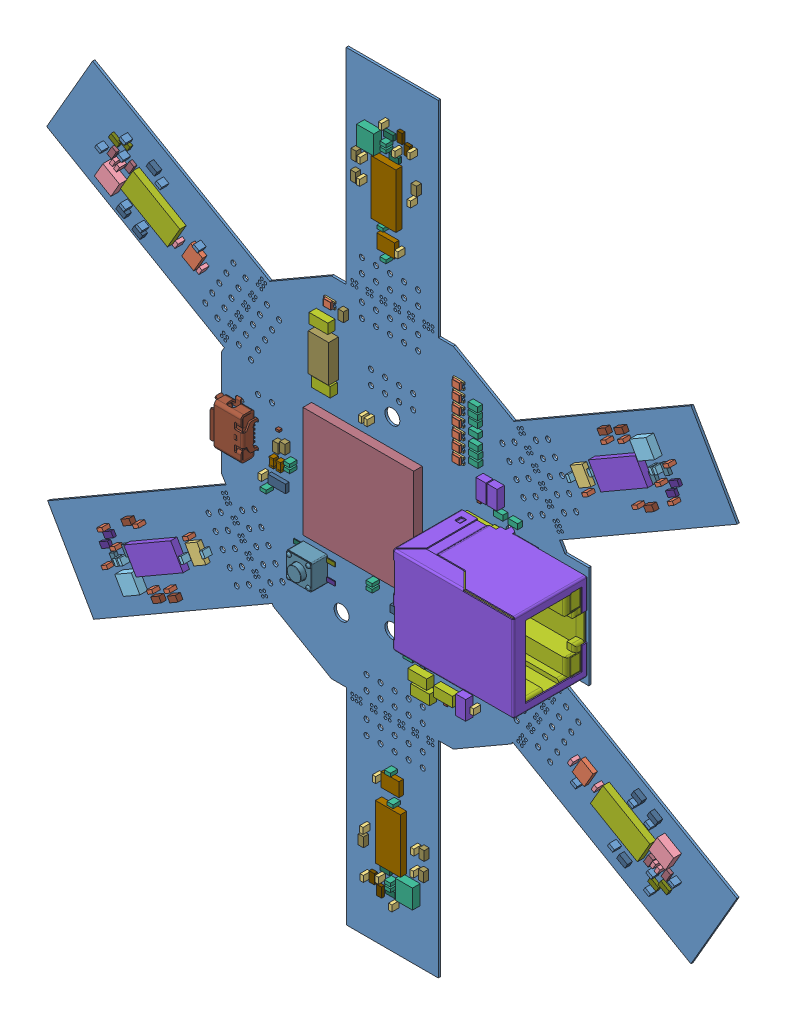
SolidWorks assembly PCB_Testplatine, configuration Standard. Lengths in mm.
Overall size (124.77 137.35 16.55).
623 component instances, 49 part files, 0 mates.
Components (placement in the parent):
- Board-1: Board [Standard] at (0 0 -0.4115) size (124.77 137.35 0.41)
- X_TDA_TDA6-1: X_TDA_TDA6 [Standard] at origin size (3.77 4.02 0.8)
  - 885545368-1: 885545368 [Standard] at (-35.3942 22.6879 0) size (3.77 4.02 0.8)
    - Extruded-1: Extruded [Standard] at origin size (3.77 4.02 0.8)
- X_TDA_TDA2-1: X_TDA_TDA2 [Standard] at origin size (3.77 4.02 0.8)
  - 885545640-1: 885545640 [Standard] at (34.8045 23.5121 0) size (3.77 4.02 0.8)
    - Extruded_2-1: Extruded_2 [Standard] at origin size (3.77 4.02 0.8)
- F1_TDA6-1: F1_TDA6 [Standard] at origin size (4.54 4.41 1.4)
  - 885544960-1: 885544960 [Standard] at (-50.1943 27.6532 0) size (4.54 4.41 1.4)
    - Extruded_3-1: Extruded_3 [Standard] at origin size (4.54 4.41 1.4)
- F1_TDA2-1: F1_TDA2 [Standard] at origin size (4.54 4.41 1.4)
  - 885545232-1: 885545232 [Standard] at (46.5047 33.8467 0) size (4.54 4.41 1.4)
    - Extruded_4-1: Extruded_4 [Standard] at origin size (4.54 4.41 1.4)
- F1_TDA1-1: F1_TDA1 [Standard] at origin size (3.1 3.45 1.4)
  - 885545096-1: 885545096 [Standard] at (-3.52 57.24 0) size (3.1 3.45 1.4)
    - Extruded_5-1: Extruded_5 [Standard] at origin size (3.1 3.45 1.4)
- T1-1: T1 [Standard] at origin size (21.84 15.88 16.55)
  - 7499010211A-1: 7499010211A [Standard] at (24.4001 -0.1251 6.7) x (0 -1 0) z (0 0 -1) size (15.88 21.84 16.55)
    - housing-1: housing [Standard] at origin size (15.48 21.44 16.35)
    - shielding-1: shielding [Standard] at origin size (15.88 21.84 16.25)
- X1-1: X1 [Standard] at origin size (3.2 2.5 0.8)
  - 885545504-1: 885545504 [Standard] at (10.5 -1.45 0) size (3.2 2.5 0.8)
    - Extruded_6-1: Extruded_6 [Standard] at origin size (3.2 2.5 0.8)
- X2-1: X2 [Standard] at origin size (3.2 1.5 0.65)
  - 885545776-1: 885545776 [Standard] at (-20.27 -5.32 0) size (3.2 1.5 0.65)
    - Extruded_7-1: Extruded_7 [Standard] at origin size (3.2 1.5 0.65)
- X_TDA_TDA1-1: X_TDA_TDA1 [Standard] at origin size (3.2 2.5 0.8)
  - 885545504-1: 885545504 [Standard] at (-0.42 41.94 0) size (3.2 2.5 0.8)
    - Extruded_6-1: Extruded_6 [Standard] at origin size (3.2 2.5 0.8)
- J1-1: J1 [Standard] at origin size (5.9 8.66 3.36)
  - 475900001-1: 475900001 [Standard] at (-26.2999 1.3001 0.26) x (0 1 0) z (1 0 0) size (8.66 3.36 5.9)
    - Open CASCADE STEP translator 6.8 1.11.1.1-1: Open CASCADE STEP translator 6.8 1.11.1.1 [Standard] at origin size (8.66 3.36 5.9)
- X_TDA_TDA5-1: X_TDA_TDA5 [Standard] at origin size (3.77 4.02 0.8)
  - 885545640-1: 885545640 [Standard] at (-34.8042 -23.4933 0) size (3.77 4.02 0.8)
    - Extruded_2-1: Extruded_2 [Standard] at origin size (3.77 4.02 0.8)
- X_TDA_TDA4-1: X_TDA_TDA4 [Standard] at origin size (3.2 2.5 0.8)
  - 885545504-1: 885545504 [Standard] at (0.38 -41.99 0) size (3.2 2.5 0.8)
    - Extruded_6-1: Extruded_6 [Standard] at origin size (3.2 2.5 0.8)
- X_TDA_TDA3-1: X_TDA_TDA3 [Standard] at origin size (3.77 4.02 0.8)
  - 885545368-1: 885545368 [Standard] at (35.1741 -22.7679 0) size (3.77 4.02 0.8)
    - Extruded-1: Extruded [Standard] at origin size (3.77 4.02 0.8)
- F1_TDA5-1: F1_TDA5 [Standard] at origin size (4.54 4.41 1.4)
  - 885545232-1: 885545232 [Standard] at (-46.5044 -33.8279 0) size (4.54 4.41 1.4)
    - Extruded_4-1: Extruded_4 [Standard] at origin size (4.54 4.41 1.4)
- F1_TDA4-1: F1_TDA4 [Standard] at origin size (3.1 3.45 1.4)
  - 885545096-1: 885545096 [Standard] at (3.48 -57.29 0) size (3.1 3.45 1.4)
    - Extruded_5-1: Extruded_5 [Standard] at origin size (3.1 3.45 1.4)
- F1_TDA3-1: F1_TDA3 [Standard] at origin size (4.54 4.41 1.4)
  - 885544960-1: 885544960 [Standard] at (49.9743 -27.7332 0) size (4.54 4.41 1.4)
    - Extruded_3-1: Extruded_3 [Standard] at origin size (4.54 4.41 1.4)
- X3-1: X3 [Standard] at origin size (2.5 3.2 0.8)
  - 885544824-1: 885544824 [Standard] at (15.2 -15.95 0) size (2.5 3.2 0.8)
    - Extruded_8-1: Extruded_8 [Standard] at origin size (2.5 3.2 0.8)
- IC3-1: IC3 [Standard] at origin size (4 4 0.85)
  - 885544688-1: 885544688 [Standard] at (8.35 -16.75 0) size (4 4 0.85)
    - Extruded_9-1: Extruded_9 [Standard] at origin size (4 4 0.85)
- S1-1: S1 [Standard] at origin size (7.5 4.5 3.8)
  - 430181038816-1: 430181038816 [Standard] at (-13.9849 -14.7149 0.01) x (1 0 0) z (0 0 1) size (7.5 4.5 3.8)
    - housing_2-1: housing_2 [Standard] at origin size (4.5 4.5 3.8)
    - pins-1: pins [Standard] at origin size (1.8 0.7 0.15)
    - pins_2-1: pins_2 [Standard] at origin size (1.8 0.7 0.15)
    - pins_3-1: pins_3 [Standard] at origin size (1.8 0.7 0.15)
    - pins_4-1: pins_4 [Standard] at origin size (1.8 0.7 0.15)
- Power-1: Power [Standard] at origin size (2 1.25 0.7)
  - WL-SMCW_0805_LED-1: WL-SMCW_0805_LED [Standard] at (-11.1648 27.3652 -0.02) x (1 0 0) z (0 0 1) size (2 1.25 0.7)
    - base-1: base [Standard] at (0.8 0 0) x (-1 0 0) z (0 0 1) size (0.4 1 0.3)
    - cover-1: cover [Standard] at (0 0 0.3) size (1.4 1.25 0.4)
    - housing_3-1: housing_3 [Standard] at origin size (2 1.25 0.3)
    - marking-1: marking [Standard] at (-0.8 0.525 0.26) size (0.4 0.48 0.04)
    - marking-2: marking [Standard] at (-0.8 -0.525 0.3) x (1 0 0) z (0 0 -1) size (0.4 0.48 0.04)
    - base_2-1: base_2 [Standard] at (-0.8 0 0) size (0.4 1 0.3)
- R26-1: R26 [Standard] at origin size (1.7 0.95 0.9)
  - 885541288-1: 885541288 [Standard] at (15.5 15.98 0) size (1.7 0.95 0.9)
    - Extruded_10-1: Extruded_10 [Standard] at origin size (1.7 0.95 0.9)
- R25-1: R25 [Standard] at origin size (1.7 0.95 0.9)
  - 885541288-1: 885541288 [Standard] at (15.5 17.26 0) size (1.7 0.95 0.9)
    - Extruded_10-1: Extruded_10 [Standard] at origin size (1.7 0.95 0.9)
- R24-1: R24 [Standard] at origin size (1.7 0.95 0.9)
  - 885541288-1: 885541288 [Standard] at (15.48 18.51 0) size (1.7 0.95 0.9)
    - Extruded_10-1: Extruded_10 [Standard] at origin size (1.7 0.95 0.9)
- D10-1: D10 [Standard] at origin size (2 1.25 0.7)
  - WL-SMCW_0805_LED-1: WL-SMCW_0805_LED [Standard] at (12.1102 14.6502 -0.02) x (1 0 0) z (0 0 1) size (2 1.25 0.7)
    - base-1: base [Standard] at (0.8 0 0) x (-1 0 0) z (0 0 1) size (0.4 1 0.3)
    - cover-1: cover [Standard] at (0 0 0.3) size (1.4 1.25 0.4)
    - housing_3-1: housing_3 [Standard] at origin size (2 1.25 0.3)
    - marking-1: marking [Standard] at (-0.8 0.525 0.26) size (0.4 0.48 0.04)
    - marking-2: marking [Standard] at (-0.8 -0.525 0.3) x (1 0 0) z (0 0 -1) size (0.4 0.48 0.04)
    - base_2-1: base_2 [Standard] at (-0.8 0 0) size (0.4 1 0.3)
- D9-1: D9 [Standard] at origin size (2 1.25 0.7)
  - WL-SMCW_0805_LED-1: WL-SMCW_0805_LED [Standard] at (12.1103 16.5697 -0.02) x (1 0 0) z (0 0 1) size (2 1.25 0.7)
    - base-1: base [Standard] at (0.8 0 0) x (-1 0 0) z (0 0 1) size (0.4 1 0.3)
    - cover-1: cover [Standard] at (0 0 0.3) size (1.4 1.25 0.4)
    - housing_3-1: housing_3 [Standard] at origin size (2 1.25 0.3)
    - marking-1: marking [Standard] at (-0.8 0.525 0.26) size (0.4 0.48 0.04)
    - marking-2: marking [Standard] at (-0.8 -0.525 0.3) x (1 0 0) z (0 0 -1) size (0.4 0.48 0.04)
    - base_2-1: base_2 [Standard] at (-0.8 0 0) size (0.4 1 0.3)
- D8-1: D8 [Standard] at origin size (2 1.25 0.7)
  - WL-SMCW_0805_LED-1: WL-SMCW_0805_LED [Standard] at (12.1002 18.5002 -0.02) x (1 0 0) z (0 0 1) size (2 1.25 0.7)
    - base-1: base [Standard] at (0.8 0 0) x (-1 0 0) z (0 0 1) size (0.4 1 0.3)
    - cover-1: cover [Standard] at (0 0 0.3) size (1.4 1.25 0.4)
    - housing_3-1: housing_3 [Standard] at origin size (2 1.25 0.3)
    - marking-1: marking [Standard] at (-0.8 0.525 0.26) size (0.4 0.48 0.04)
    - marking-2: marking [Standard] at (-0.8 -0.525 0.3) x (1 0 0) z (0 0 -1) size (0.4 0.48 0.04)
    - base_2-1: base_2 [Standard] at (-0.8 0 0) size (0.4 1 0.3)
- TDA5340_TDA6-1: TDA5340_TDA6 [Standard] at origin size (10.74 8.8 1.15)
  - 885544416-1: 885544416 [Standard] at (-42.5822 26.8379 0.05) size (10.74 8.8 1.15)
    - Extruded_11-1: Extruded_11 [Standard] at origin size (10.74 8.8 1.15)
- TDA5340_TDA5-1: TDA5340_TDA5 [Standard] at origin size (10.74 8.8 1.15)
  - 885544280-1: 885544280 [Standard] at (-41.9922 -27.6432 0.05) size (10.74 8.8 1.15)
    - Extruded_12-1: Extruded_12 [Standard] at origin size (10.74 8.8 1.15)
- TDA5340_TDA4-1: TDA5340_TDA4 [Standard] at origin size (4.5 9.8 1.15)
  - 885542512-1: 885542512 [Standard] at (0.38 -50.29 0.05) size (4.5 9.8 1.15)
    - Extruded_13-1: Extruded_13 [Standard] at origin size (4.5 9.8 1.15)
- TDA5340_TDA3-1: TDA5340_TDA3 [Standard] at origin size (10.74 8.8 1.15)
  - 885544416-1: 885544416 [Standard] at (42.3622 -26.9179 0.05) size (10.74 8.8 1.15)
    - Extruded_11-1: Extruded_11 [Standard] at origin size (10.74 8.8 1.15)
- TDA5340_TDA2-1: TDA5340_TDA2 [Standard] at origin size (10.74 8.8 1.15)
  - 885544280-1: 885544280 [Standard] at (41.9925 27.6621 0.05) size (10.74 8.8 1.15)
    - Extruded_12-1: Extruded_12 [Standard] at origin size (10.74 8.8 1.15)
- R3_TDA6-1: R3_TDA6 [Standard] at origin size (1.95 1.67 0.9)
  - 885544144-1: 885544144 [Standard] at (-42.6285 32.8576 0) size (1.95 1.67 0.9)
    - Extruded_14-1: Extruded_14 [Standard] at origin size (1.95 1.67 0.9)
- R3_TDA5-1: R3_TDA5 [Standard] at origin size (1.95 1.67 0.9)
  - 885544008-1: 885544008 [Standard] at (-47.2285 -24.6736 0) size (1.95 1.67 0.9)
    - Extruded_15-1: Extruded_15 [Standard] at origin size (1.95 1.67 0.9)
- R3_TDA4-1: R3_TDA4 [Standard] at origin size (0.95 1.7 0.9)
  - 885541560-1: 885541560 [Standard] at (-4.81 -53.34 0) size (0.95 1.7 0.9)
    - Extruded_16-1: Extruded_16 [Standard] at origin size (0.95 1.7 0.9)
- R3_TDA3-1: R3_TDA3 [Standard] at origin size (1.95 1.67 0.9)
  - 885544144-1: 885544144 [Standard] at (42.4085 -32.9376 0) size (1.95 1.67 0.9)
    - Extruded_14-1: Extruded_14 [Standard] at origin size (1.95 1.67 0.9)
- R3_TDA2-1: R3_TDA2 [Standard] at origin size (1.95 1.67 0.9)
  - 885544008-1: 885544008 [Standard] at (47.2288 24.6924 0) size (1.95 1.67 0.9)
    - Extruded_15-1: Extruded_15 [Standard] at origin size (1.95 1.67 0.9)
- R2_TDA6-1: R2_TDA6 [Standard] at origin size (1.95 1.67 0.9)
  - 885544144-1: 885544144 [Standard] at (-48.1169 23.4516 0) size (1.95 1.67 0.9)
    - Extruded_14-1: Extruded_14 [Standard] at origin size (1.95 1.67 0.9)
- R2_TDA5-1: R2_TDA5 [Standard] at origin size (1.95 1.67 0.9)
  - 885544008-1: 885544008 [Standard] at (-41.8269 -34.1296 0) size (1.95 1.67 0.9)
    - Extruded_15-1: Extruded_15 [Standard] at origin size (1.95 1.67 0.9)
- R2_TDA4-1: R2_TDA4 [Standard] at origin size (0.95 1.7 0.9)
  - 885541560-1: 885541560 [Standard] at (6.08 -53.39 0) size (0.95 1.7 0.9)
    - Extruded_16-1: Extruded_16 [Standard] at origin size (0.95 1.7 0.9)
- R2_TDA3-1: R2_TDA3 [Standard] at origin size (1.95 1.67 0.9)
  - 885544144-1: 885544144 [Standard] at (47.8969 -23.5316 0) size (1.95 1.67 0.9)
    - Extruded_14-1: Extruded_14 [Standard] at origin size (1.95 1.67 0.9)
- R2_TDA2-1: R2_TDA2 [Standard] at origin size (1.95 1.67 0.9)
  - 885544008-1: 885544008 [Standard] at (41.8271 34.1484 0) size (1.95 1.67 0.9)
    - Extruded_15-1: Extruded_15 [Standard] at origin size (1.95 1.67 0.9)
- R1_TDA6-1: R1_TDA6 [Standard] at origin size (1.95 1.67 0.9)
  - 885544144-1: 885544144 [Standard] at (-45.2224 21.6649 0) size (1.95 1.67 0.9)
    - Extruded_14-1: Extruded_14 [Standard] at origin size (1.95 1.67 0.9)
- R1_TDA5-1: R1_TDA5 [Standard] at origin size (1.95 1.67 0.9)
  - 885544008-1: 885544008 [Standard] at (-38.8324 -32.5162 0) size (1.95 1.67 0.9)
    - Extruded_15-1: Extruded_15 [Standard] at origin size (1.95 1.67 0.9)
- R1_TDA4-1: R1_TDA4 [Standard] at origin size (0.95 1.7 0.9)
  - 885541560-1: 885541560 [Standard] at (6.18 -49.99 0) size (0.95 1.7 0.9)
    - Extruded_16-1: Extruded_16 [Standard] at origin size (0.95 1.7 0.9)
- R1_TDA3-1: R1_TDA3 [Standard] at origin size (1.95 1.67 0.9)
  - 885544144-1: 885544144 [Standard] at (45.0024 -21.7449 0) size (1.95 1.67 0.9)
    - Extruded_14-1: Extruded_14 [Standard] at origin size (1.95 1.67 0.9)
- R1_TDA2-1: R1_TDA2 [Standard] at origin size (1.95 1.67 0.9)
  - 885544008-1: 885544008 [Standard] at (38.8326 32.535 0) size (1.95 1.67 0.9)
    - Extruded_15-1: Extruded_15 [Standard] at origin size (1.95 1.67 0.9)
- L4_TDA6-1: L4_TDA6 [Standard] at origin size (1.7 1.99 0.55)
  - 885543600-1: 885543600 [Standard] at (-50.1898 31.4611 0) size (1.7 1.99 0.55)
    - Extruded_17-1: Extruded_17 [Standard] at origin size (1.7 1.99 0.55)
- L4_TDA5-1: L4_TDA5 [Standard] at origin size (1.7 1.99 0.55)
  - 885543464-1: 885543464 [Standard] at (-49.7998 -31.9201 0) size (1.7 1.99 0.55)
    - Extruded_18-1: Extruded_18 [Standard] at origin size (1.7 1.99 0.55)
- L4_TDA4-1: L4_TDA4 [Standard] at origin size (1.75 0.95 0.55)
  - 885542648-1: 885542648 [Standard] at (0.18 -59.19 0) size (1.75 0.95 0.55)
    - Extruded_19-1: Extruded_19 [Standard] at origin size (1.75 0.95 0.55)
- L4_TDA3-1: L4_TDA3 [Standard] at origin size (1.7 1.99 0.55)
  - 885543600-1: 885543600 [Standard] at (49.9698 -31.5411 0) size (1.7 1.99 0.55)
    - Extruded_17-1: Extruded_17 [Standard] at origin size (1.7 1.99 0.55)
- L4_TDA2-1: L4_TDA2 [Standard] at origin size (1.7 1.99 0.55)
  - 885543464-1: 885543464 [Standard] at (49.8001 31.9389 0) size (1.7 1.99 0.55)
    - Extruded_18-1: Extruded_18 [Standard] at origin size (1.7 1.99 0.55)
- L3_TDA6-1: L3_TDA6 [Standard] at origin size (1.99 1.7 0.55)
  - 885543872-1: 885543872 [Standard] at (-47.8899 34.0246 0) size (1.99 1.7 0.55)
    - Extruded_20-1: Extruded_20 [Standard] at origin size (1.99 1.7 0.55)
- L3_TDA5-1: L3_TDA5 [Standard] at origin size (1.99 1.7 0.55)
  - 885543736-1: 885543736 [Standard] at (-50.8699 -28.6466 0) size (1.99 1.7 0.55)
    - Extruded_21-1: Extruded_21 [Standard] at origin size (1.99 1.7 0.55)
- L3_TDA4-1: L3_TDA4 [Standard] at origin size (0.95 1.75 0.55)
  - 885542784-1: 885542784 [Standard] at (-3.19 -58.48 0) size (0.95 1.75 0.55)
    - Extruded_22-1: Extruded_22 [Standard] at origin size (0.95 1.75 0.55)
- L3_TDA3-1: L3_TDA3 [Standard] at origin size (1.99 1.7 0.55)
  - 885543872-1: 885543872 [Standard] at (47.6699 -34.1046 0) size (1.99 1.7 0.55)
    - Extruded_20-1: Extruded_20 [Standard] at origin size (1.99 1.7 0.55)
- L3_TDA2-1: L3_TDA2 [Standard] at origin size (1.99 1.7 0.55)
  - 885543736-1: 885543736 [Standard] at (50.8702 28.6654 0) size (1.99 1.7 0.55)
    - Extruded_21-1: Extruded_21 [Standard] at origin size (1.99 1.7 0.55)
- L2_TDA6-1: L2_TDA6 [Standard] at origin size (1.99 1.7 0.55)
  - 885543872-1: 885543872 [Standard] at (-49.792 33.6101 0) size (1.99 1.7 0.55)
    - Extruded_20-1: Extruded_20 [Standard] at origin size (1.99 1.7 0.55)
- L2_TDA5-1: L2_TDA5 [Standard] at origin size (1.99 1.7 0.55)
  - 885543736-1: 885543736 [Standard] at (-51.462 -30.5011 0) size (1.99 1.7 0.55)
    - Extruded_21-1: Extruded_21 [Standard] at origin size (1.99 1.7 0.55)
- L2_TDA4-1: L2_TDA4 [Standard] at origin size (0.95 1.75 0.55)
  - 885542784-1: 885542784 [Standard] at (-1.88 -59.92 0) size (0.95 1.75 0.55)
    - Extruded_22-1: Extruded_22 [Standard] at origin size (0.95 1.75 0.55)
- L2_TDA3-1: L2_TDA3 [Standard] at origin size (1.99 1.7 0.55)
  - 885543872-1: 885543872 [Standard] at (49.572 -33.6901 0) size (1.99 1.7 0.55)
    - Extruded_20-1: Extruded_20 [Standard] at origin size (1.99 1.7 0.55)
- L2_TDA2-1: L2_TDA2 [Standard] at origin size (1.99 1.7 0.55)
  - 885543736-1: 885543736 [Standard] at (51.4623 30.5199 0) size (1.99 1.7 0.55)
    - Extruded_21-1: Extruded_21 [Standard] at origin size (1.99 1.7 0.55)
- L1_TDA6-1: L1_TDA6 [Standard] at origin size (1.7 1.99 0.55)
  - 885543600-1: 885543600 [Standard] at (-47.0051 30.7771 0) size (1.7 1.99 0.55)
    - Extruded_17-1: Extruded_17 [Standard] at origin size (1.7 1.99 0.55)
- L1_TDA5-1: L1_TDA5 [Standard] at origin size (1.7 1.99 0.55)
  - 885543464-1: 885543464 [Standard] at (-47.6151 -29.504 0) size (1.7 1.99 0.55)
    - Extruded_18-1: Extruded_18 [Standard] at origin size (1.7 1.99 0.55)
- L1_TDA4-1: L1_TDA4 [Standard] at origin size (1.75 0.95 0.55)
  - 885542648-1: 885542648 [Standard] at (-0.82 -56.09 0) size (1.75 0.95 0.55)
    - Extruded_19-1: Extruded_19 [Standard] at origin size (1.75 0.95 0.55)
- L1_TDA3-1: L1_TDA3 [Standard] at origin size (1.7 1.99 0.55)
  - 885543600-1: 885543600 [Standard] at (46.7851 -30.8571 0) size (1.7 1.99 0.55)
    - Extruded_17-1: Extruded_17 [Standard] at origin size (1.7 1.99 0.55)
- L1_TDA2-1: L1_TDA2 [Standard] at origin size (1.7 1.99 0.55)
  - 885543464-1: 885543464 [Standard] at (47.6154 29.5229 0) size (1.7 1.99 0.55)
    - Extruded_18-1: Extruded_18 [Standard] at origin size (1.7 1.99 0.55)
- C31_TDA6-1: C31_TDA6 [Standard] at origin size (1.25 1.07 1.3)
  - 885543056-1: 885543056 [Standard] at (-51.8712 31.5889 0) size (1.25 1.07 1.3)
    - Extruded_23-1: Extruded_23 [Standard] at origin size (1.25 1.07 1.3)
- C31_TDA5-1: C31_TDA5 [Standard] at origin size (1.25 1.07 1.3)
  - 885542920-1: 885542920 [Standard] at (-50.7512 -33.3123 0) size (1.25 1.07 1.3)
    - Extruded_24-1: Extruded_24 [Standard] at origin size (1.25 1.07 1.3)
- C31_TDA4-1: C31_TDA4 [Standard] at origin size (0.6 1.1 1.3)
  - 885542376-1: 885542376 [Standard] at (0.91 -60.71 0) size (0.6 1.1 1.3)
    - Extruded_25-1: Extruded_25 [Standard] at origin size (0.6 1.1 1.3)
- C31_TDA3-1: C31_TDA3 [Standard] at origin size (1.25 1.07 1.3)
  - 885543056-1: 885543056 [Standard] at (51.6512 -31.6689 0) size (1.25 1.07 1.3)
    - Extruded_23-1: Extruded_23 [Standard] at origin size (1.25 1.07 1.3)
- C31_TDA2-1: C31_TDA2 [Standard] at origin size (1.25 1.07 1.3)
  - 885542920-1: 885542920 [Standard] at (50.7515 33.3311 0) size (1.25 1.07 1.3)
    - Extruded_24-1: Extruded_24 [Standard] at origin size (1.25 1.07 1.3)
- C30_TDA6-1: C30_TDA6 [Standard] at origin size (1.25 1.07 1.3)
  - 885543056-1: 885543056 [Standard] at (-47.5295 35.0289 0) size (1.25 1.07 1.3)
    - Extruded_23-1: Extruded_23 [Standard] at origin size (1.25 1.07 1.3)
- C30_TDA5-1: C30_TDA5 [Standard] at origin size (1.25 1.07 1.3)
  - 885542920-1: 885542920 [Standard] at (-51.5595 -27.8323 0) size (1.25 1.07 1.3)
    - Extruded_24-1: Extruded_24 [Standard] at origin size (1.25 1.07 1.3)
- C30_TDA4-1: C30_TDA4 [Standard] at origin size (0.6 1.1 1.3)
  - 885542376-1: 885542376 [Standard] at (-4.24 -58.67 0) size (0.6 1.1 1.3)
    - Extruded_25-1: Extruded_25 [Standard] at origin size (0.6 1.1 1.3)
- C30_TDA3-1: C30_TDA3 [Standard] at origin size (1.25 1.07 1.3)
  - 885543056-1: 885543056 [Standard] at (47.3095 -35.1089 0) size (1.25 1.07 1.3)
    - Extruded_23-1: Extruded_23 [Standard] at origin size (1.25 1.07 1.3)
- C30_TDA2-1: C30_TDA2 [Standard] at origin size (1.25 1.07 1.3)
  - 885542920-1: 885542920 [Standard] at (51.5598 27.8511 0) size (1.25 1.07 1.3)
    - Extruded_24-1: Extruded_24 [Standard] at origin size (1.25 1.07 1.3)
- C29_TDA6-1: C29_TDA6 [Standard] at origin size (1.07 1.25 1.3)
  - 885543328-1: 885543328 [Standard] at (-49.3371 30.7379 0) size (1.07 1.25 1.3)
    - Extruded_26-1: Extruded_26 [Standard] at origin size (1.07 1.25 1.3)
- C29_TDA5-1: C29_TDA5 [Standard] at origin size (1.07 1.25 1.3)
  - 885543192-1: 885543192 [Standard] at (-48.7472 -31.5432 0) size (1.07 1.25 1.3)
    - Extruded_27-1: Extruded_27 [Standard] at origin size (1.07 1.25 1.3)
- C29_TDA4-1: C29_TDA4 [Standard] at origin size (1.1 0.6 1.3)
  - 885542240-1: 885542240 [Standard] at (0.38 -58.09 0) size (1.1 0.6 1.3)
    - Extruded_28-1: Extruded_28 [Standard] at origin size (1.1 0.6 1.3)
- C29_TDA3-1: C29_TDA3 [Standard] at origin size (1.07 1.25 1.3)
  - 885543328-1: 885543328 [Standard] at (49.1171 -30.8179 0) size (1.07 1.25 1.3)
    - Extruded_26-1: Extruded_26 [Standard] at origin size (1.07 1.25 1.3)
- C29_TDA2-1: C29_TDA2 [Standard] at origin size (1.07 1.25 1.3)
  - 885543192-1: 885543192 [Standard] at (48.7475 31.5621 0) size (1.07 1.25 1.3)
    - Extruded_27-1: Extruded_27 [Standard] at origin size (1.07 1.25 1.3)
- C28_TDA6-1: C28_TDA6 [Standard] at origin size (1.07 1.25 1.3)
  - 885543328-1: 885543328 [Standard] at (-48.5577 30.2879 0) size (1.07 1.25 1.3)
    - Extruded_26-1: Extruded_26 [Standard] at origin size (1.07 1.25 1.3)
- C28_TDA5-1: C28_TDA5 [Standard] at origin size (1.07 1.25 1.3)
  - 885543192-1: 885543192 [Standard] at (-47.9677 -31.0933 0) size (1.07 1.25 1.3)
    - Extruded_27-1: Extruded_27 [Standard] at origin size (1.07 1.25 1.3)
- C28_TDA4-1: C28_TDA4 [Standard] at origin size (1.1 0.6 1.3)
  - 885542240-1: 885542240 [Standard] at (0.38 -57.19 0) size (1.1 0.6 1.3)
    - Extruded_28-1: Extruded_28 [Standard] at origin size (1.1 0.6 1.3)
- C28_TDA3-1: C28_TDA3 [Standard] at origin size (1.07 1.25 1.3)
  - 885543328-1: 885543328 [Standard] at (48.3377 -30.3679 0) size (1.07 1.25 1.3)
    - Extruded_26-1: Extruded_26 [Standard] at origin size (1.07 1.25 1.3)
- C28_TDA2-1: C28_TDA2 [Standard] at origin size (1.07 1.25 1.3)
  - 885543192-1: 885543192 [Standard] at (47.968 31.1121 0) size (1.07 1.25 1.3)
    - Extruded_27-1: Extruded_27 [Standard] at origin size (1.07 1.25 1.3)
- C27_TDA6-1: C27_TDA6 [Standard] at origin size (1.25 1.07 1.3)
  - 885543056-1: 885543056 [Standard] at (-47.9541 32.1333 0) size (1.25 1.07 1.3)
    - Extruded_23-1: Extruded_23 [Standard] at origin size (1.25 1.07 1.3)
- C27_TDA5-1: C27_TDA5 [Standard] at origin size (1.25 1.07 1.3)
  - 885542920-1: 885542920 [Standard] at (-49.2641 -29.6478 0) size (1.25 1.07 1.3)
    - Extruded_24-1: Extruded_24 [Standard] at origin size (1.25 1.07 1.3)
- C27_TDA4-1: C27_TDA4 [Standard] at origin size (0.6 1.1 1.3)
  - 885542376-1: 885542376 [Standard] at (-1.52 -57.59 0) size (0.6 1.1 1.3)
    - Extruded_25-1: Extruded_25 [Standard] at origin size (0.6 1.1 1.3)
- C27_TDA3-1: C27_TDA3 [Standard] at origin size (1.25 1.07 1.3)
  - 885543056-1: 885543056 [Standard] at (47.7341 -32.2133 0) size (1.25 1.07 1.3)
    - Extruded_23-1: Extruded_23 [Standard] at origin size (1.25 1.07 1.3)
- C27_TDA2-1: C27_TDA2 [Standard] at origin size (1.25 1.07 1.3)
  - 885542920-1: 885542920 [Standard] at (49.2644 29.6666 0) size (1.25 1.07 1.3)
    - Extruded_24-1: Extruded_24 [Standard] at origin size (1.25 1.07 1.3)
- C26_TDA6-1: C26_TDA6 [Standard] at origin size (1.07 1.25 1.3)
  - 885543328-1: 885543328 [Standard] at (-33.6621 21.6879 0) size (1.07 1.25 1.3)
    - Extruded_26-1: Extruded_26 [Standard] at origin size (1.07 1.25 1.3)
- C26_TDA5-1: C26_TDA5 [Standard] at origin size (1.07 1.25 1.3)
  - 885543192-1: 885543192 [Standard] at (-33.0721 -22.4933 0) size (1.07 1.25 1.3)
    - Extruded_27-1: Extruded_27 [Standard] at origin size (1.07 1.25 1.3)
- C26_TDA4-1: C26_TDA4 [Standard] at origin size (1.1 0.6 1.3)
  - 885542240-1: 885542240 [Standard] at (0.38 -39.99 0) size (1.1 0.6 1.3)
    - Extruded_28-1: Extruded_28 [Standard] at origin size (1.1 0.6 1.3)
- C26_TDA3-1: C26_TDA3 [Standard] at origin size (1.07 1.25 1.3)
  - 885543328-1: 885543328 [Standard] at (33.4421 -21.7679 0) size (1.07 1.25 1.3)
    - Extruded_26-1: Extruded_26 [Standard] at origin size (1.07 1.25 1.3)
- C26_TDA2-1: C26_TDA2 [Standard] at origin size (1.07 1.25 1.3)
  - 885543192-1: 885543192 [Standard] at (33.0724 22.5121 0) size (1.07 1.25 1.3)
    - Extruded_27-1: Extruded_27 [Standard] at origin size (1.07 1.25 1.3)
- C25_TDA6-1: C25_TDA6 [Standard] at origin size (1.25 1.07 1.3)
  - 885543056-1: 885543056 [Standard] at (-34.2808 24.8163 0) size (1.25 1.07 1.3)
    - Extruded_23-1: Extruded_23 [Standard] at origin size (1.25 1.07 1.3)
- C25_TDA5-1: C25_TDA5 [Standard] at origin size (1.25 1.07 1.3)
  - 885542920-1: 885542920 [Standard] at (-36.0907 -21.4648 0) size (1.25 1.07 1.3)
    - Extruded_24-1: Extruded_24 [Standard] at origin size (1.25 1.07 1.3)
- C25_TDA4-1: C25_TDA4 [Standard] at origin size (0.6 1.1 1.3)
  - 885542376-1: 885542376 [Standard] at (-2.02 -42.09 0) size (0.6 1.1 1.3)
    - Extruded_25-1: Extruded_25 [Standard] at origin size (0.6 1.1 1.3)
- C25_TDA3-1: C25_TDA3 [Standard] at origin size (1.25 1.07 1.3)
  - 885543056-1: 885543056 [Standard] at (34.0607 -24.8964 0) size (1.25 1.07 1.3)
    - Extruded_23-1: Extruded_23 [Standard] at origin size (1.25 1.07 1.3)
- C25_TDA2-1: C25_TDA2 [Standard] at origin size (1.25 1.07 1.3)
  - 885542920-1: 885542920 [Standard] at (36.091 21.4836 0) size (1.25 1.07 1.3)
    - Extruded_24-1: Extruded_24 [Standard] at origin size (1.25 1.07 1.3)
- C24_TDA6-1: C24_TDA6 [Standard] at origin size (1.07 1.25 1.3)
  - 885543328-1: 885543328 [Standard] at (-37.9824 23.6049 0) size (1.07 1.25 1.3)
    - Extruded_26-1: Extruded_26 [Standard] at origin size (1.07 1.25 1.3)
- C24_TDA5-1: C24_TDA5 [Standard] at origin size (1.07 1.25 1.3)
  - 885543192-1: 885543192 [Standard] at (-36.8924 -25.2763 0) size (1.07 1.25 1.3)
    - Extruded_27-1: Extruded_27 [Standard] at origin size (1.07 1.25 1.3)
- C24_TDA4-1: C24_TDA4 [Standard] at origin size (1.1 0.6 1.3)
  - 885542240-1: 885542240 [Standard] at (0.88 -44.69 0) size (1.1 0.6 1.3)
    - Extruded_28-1: Extruded_28 [Standard] at origin size (1.1 0.6 1.3)
- C24_TDA3-1: C24_TDA3 [Standard] at origin size (1.07 1.25 1.3)
  - 885543328-1: 885543328 [Standard] at (37.7624 -23.6849 0) size (1.07 1.25 1.3)
    - Extruded_26-1: Extruded_26 [Standard] at origin size (1.07 1.25 1.3)
- C24_TDA2-1: C24_TDA2 [Standard] at origin size (1.07 1.25 1.3)
  - 885543192-1: 885543192 [Standard] at (36.8927 25.2951 0) size (1.07 1.25 1.3)
    - Extruded_27-1: Extruded_27 [Standard] at origin size (1.07 1.25 1.3)
- C23_TDA6-1: C23_TDA6 [Standard] at origin size (1.25 1.07 1.3)
  - 885543056-1: 885543056 [Standard] at (-41.0166 31.3495 0) size (1.25 1.07 1.3)
    - Extruded_23-1: Extruded_23 [Standard] at origin size (1.25 1.07 1.3)
- C23_TDA5-1: C23_TDA5 [Standard] at origin size (1.25 1.07 1.3)
  - 885542920-1: 885542920 [Standard] at (-45.1166 -24.0316 0) size (1.25 1.07 1.3)
    - Extruded_24-1: Extruded_24 [Standard] at origin size (1.25 1.07 1.3)
- C23_TDA4-1: C23_TDA4 [Standard] at origin size (0.6 1.1 1.3)
  - 885542376-1: 885542376 [Standard] at (-4.31 -51.19 0) size (0.6 1.1 1.3)
    - Extruded_25-1: Extruded_25 [Standard] at origin size (0.6 1.1 1.3)
- C23_TDA3-1: C23_TDA3 [Standard] at origin size (1.25 1.07 1.3)
  - 885543056-1: 885543056 [Standard] at (40.7966 -31.4296 0) size (1.25 1.07 1.3)
    - Extruded_23-1: Extruded_23 [Standard] at origin size (1.25 1.07 1.3)
- C23_TDA2-1: C23_TDA2 [Standard] at origin size (1.25 1.07 1.3)
  - 885542920-1: 885542920 [Standard] at (45.1169 24.0504 0) size (1.25 1.07 1.3)
    - Extruded_24-1: Extruded_24 [Standard] at origin size (1.25 1.07 1.3)
- C22_TDA6-1: C22_TDA6 [Standard] at origin size (1.25 1.07 1.3)
  - 885543056-1: 885543056 [Standard] at (-47.5534 24.6274 0) size (1.25 1.07 1.3)
    - Extruded_23-1: Extruded_23 [Standard] at origin size (1.25 1.07 1.3)
- C22_TDA5-1: C22_TDA5 [Standard] at origin size (1.25 1.07 1.3)
  - 885542920-1: 885542920 [Standard] at (-42.5634 -33.0538 0) size (1.25 1.07 1.3)
    - Extruded_24-1: Extruded_24 [Standard] at origin size (1.25 1.07 1.3)
- C22_TDA4-1: C22_TDA4 [Standard] at origin size (0.6 1.1 1.3)
  - 885542376-1: 885542376 [Standard] at (4.78 -53.49 0) size (0.6 1.1 1.3)
    - Extruded_25-1: Extruded_25 [Standard] at origin size (0.6 1.1 1.3)
- C22_TDA3-1: C22_TDA3 [Standard] at origin size (1.25 1.07 1.3)
  - 885543056-1: 885543056 [Standard] at (47.3334 -24.7074 0) size (1.25 1.07 1.3)
    - Extruded_23-1: Extruded_23 [Standard] at origin size (1.25 1.07 1.3)
- C22_TDA2-1: C22_TDA2 [Standard] at origin size (1.25 1.07 1.3)
  - 885542920-1: 885542920 [Standard] at (42.5637 33.0726 0) size (1.25 1.07 1.3)
    - Extruded_24-1: Extruded_24 [Standard] at origin size (1.25 1.07 1.3)
- C21_TDA6-1: C21_TDA6 [Standard] at origin size (1.25 1.07 1.3)
  - 885543056-1: 885543056 [Standard] at (-44.5724 22.7908 0) size (1.25 1.07 1.3)
    - Extruded_23-1: Extruded_23 [Standard] at origin size (1.25 1.07 1.3)
- C21_TDA5-1: C21_TDA5 [Standard] at origin size (1.25 1.07 1.3)
  - 885542920-1: 885542920 [Standard] at (-39.4823 -31.3904 0) size (1.25 1.07 1.3)
    - Extruded_24-1: Extruded_24 [Standard] at origin size (1.25 1.07 1.3)
- C21_TDA4-1: C21_TDA4 [Standard] at origin size (0.6 1.1 1.3)
  - 885542376-1: 885542376 [Standard] at (4.88 -49.99 0) size (0.6 1.1 1.3)
    - Extruded_25-1: Extruded_25 [Standard] at origin size (0.6 1.1 1.3)
- C21_TDA3-1: C21_TDA3 [Standard] at origin size (1.25 1.07 1.3)
  - 885543056-1: 885543056 [Standard] at (44.3524 -22.8708 0) size (1.25 1.07 1.3)
    - Extruded_23-1: Extruded_23 [Standard] at origin size (1.25 1.07 1.3)
- C21_TDA2-1: C21_TDA2 [Standard] at origin size (1.25 1.07 1.3)
  - 885542920-1: 885542920 [Standard] at (39.4826 31.4092 0) size (1.25 1.07 1.3)
    - Extruded_24-1: Extruded_24 [Standard] at origin size (1.25 1.07 1.3)
- C1-1: C1 [Standard] at origin size (0.6 1.1 1.3)
  - 885542376-1: 885542376 [Standard] at (-3.55 13 0) size (0.6 1.1 1.3)
    - Extruded_25-1: Extruded_25 [Standard] at origin size (0.6 1.1 1.3)
- C2-1: C2 [Standard] at origin size (1.1 0.6 1.3)
  - 885542240-1: 885542240 [Standard] at (8.85 -4.7 0) size (1.1 0.6 1.3)
    - Extruded_28-1: Extruded_28 [Standard] at origin size (1.1 0.6 1.3)
- C3-1: C3 [Standard] at origin size (1.1 0.6 1.3)
  - 885542240-1: 885542240 [Standard] at (-2.9 -11.95 0) size (1.1 0.6 1.3)
    - Extruded_28-1: Extruded_28 [Standard] at origin size (1.1 0.6 1.3)
- C4-1: C4 [Standard] at origin size (1.1 0.6 1.3)
  - 885542240-1: 885542240 [Standard] at (-17.8 -1.6 0) size (1.1 0.6 1.3)
    - Extruded_28-1: Extruded_28 [Standard] at origin size (1.1 0.6 1.3)
- C5-1: C5 [Standard] at origin size (1.1 0.6 1.3)
  - 885542240-1: 885542240 [Standard] at (-17.8 -0.7 0) size (1.1 0.6 1.3)
    - Extruded_28-1: Extruded_28 [Standard] at origin size (1.1 0.6 1.3)
- C6-1: C6 [Standard] at origin size (1.1 0.6 1.3)
  - 885542240-1: 885542240 [Standard] at (-2.9 -12.85 0) size (1.1 0.6 1.3)
    - Extruded_28-1: Extruded_28 [Standard] at origin size (1.1 0.6 1.3)
- C7-1: C7 [Standard] at origin size (0.6 1.1 1.3)
  - 885542376-1: 885542376 [Standard] at (7.5 -2.9 0) size (0.6 1.1 1.3)
    - Extruded_25-1: Extruded_25 [Standard] at origin size (0.6 1.1 1.3)
- C8-1: C8 [Standard] at origin size (0.6 1.1 1.3)
  - 885542376-1: 885542376 [Standard] at (-4.55 13 0) size (0.6 1.1 1.3)
    - Extruded_25-1: Extruded_25 [Standard] at origin size (0.6 1.1 1.3)
- C9-1: C9 [Standard] at origin size (1.1 0.6 1.3)
  - 885542240-1: 885542240 [Standard] at (10.65 -3.45 0) size (1.1 0.6 1.3)
    - Extruded_28-1: Extruded_28 [Standard] at origin size (1.1 0.6 1.3)
- C10-1: C10 [Standard] at origin size (1.1 0.6 1.3)
  - 885542240-1: 885542240 [Standard] at (9.75 0.55 0) size (1.1 0.6 1.3)
    - Extruded_28-1: Extruded_28 [Standard] at origin size (1.1 0.6 1.3)
- C11-1: C11 [Standard] at origin size (0.6 1.1 1.3)
  - 885542376-1: 885542376 [Standard] at (-22.66 -5.13 0) size (0.6 1.1 1.3)
    - Extruded_25-1: Extruded_25 [Standard] at origin size (0.6 1.1 1.3)
- C12-1: C12 [Standard] at origin size (1.1 0.6 1.3)
  - 885542240-1: 885542240 [Standard] at (-22.06 -6.91 0) size (1.1 0.6 1.3)
    - Extruded_28-1: Extruded_28 [Standard] at origin size (1.1 0.6 1.3)
- C21_TDA1-1: C21_TDA1 [Standard] at origin size (0.6 1.1 1.3)
  - 885542376-1: 885542376 [Standard] at (-4.92 49.94 0) size (0.6 1.1 1.3)
    - Extruded_25-1: Extruded_25 [Standard] at origin size (0.6 1.1 1.3)
- C22_TDA1-1: C22_TDA1 [Standard] at origin size (0.6 1.1 1.3)
  - 885542376-1: 885542376 [Standard] at (-4.82 53.44 0) size (0.6 1.1 1.3)
    - Extruded_25-1: Extruded_25 [Standard] at origin size (0.6 1.1 1.3)
- C23_TDA1-1: C23_TDA1 [Standard] at origin size (0.6 1.1 1.3)
  - 885542376-1: 885542376 [Standard] at (4.27 51.14 0) size (0.6 1.1 1.3)
    - Extruded_25-1: Extruded_25 [Standard] at origin size (0.6 1.1 1.3)
- C24_TDA1-1: C24_TDA1 [Standard] at origin size (1.1 0.6 1.3)
  - 885542240-1: 885542240 [Standard] at (-0.92 44.64 0) size (1.1 0.6 1.3)
    - Extruded_28-1: Extruded_28 [Standard] at origin size (1.1 0.6 1.3)
- C25_TDA1-1: C25_TDA1 [Standard] at origin size (0.6 1.1 1.3)
  - 885542376-1: 885542376 [Standard] at (1.98 42.04 0) size (0.6 1.1 1.3)
    - Extruded_25-1: Extruded_25 [Standard] at origin size (0.6 1.1 1.3)
- C26_TDA1-1: C26_TDA1 [Standard] at origin size (1.1 0.6 1.3)
  - 885542240-1: 885542240 [Standard] at (-0.42 39.94 0) size (1.1 0.6 1.3)
    - Extruded_28-1: Extruded_28 [Standard] at origin size (1.1 0.6 1.3)
- C27_TDA1-1: C27_TDA1 [Standard] at origin size (0.6 1.1 1.3)
  - 885542376-1: 885542376 [Standard] at (1.48 57.54 0) size (0.6 1.1 1.3)
    - Extruded_25-1: Extruded_25 [Standard] at origin size (0.6 1.1 1.3)
- C28_TDA1-1: C28_TDA1 [Standard] at origin size (1.1 0.6 1.3)
  - 885542240-1: 885542240 [Standard] at (-0.42 57.14 0) size (1.1 0.6 1.3)
    - Extruded_28-1: Extruded_28 [Standard] at origin size (1.1 0.6 1.3)
- C29_TDA1-1: C29_TDA1 [Standard] at origin size (1.1 0.6 1.3)
  - 885542240-1: 885542240 [Standard] at (-0.42 58.04 0) size (1.1 0.6 1.3)
    - Extruded_28-1: Extruded_28 [Standard] at origin size (1.1 0.6 1.3)
- C30_TDA1-1: C30_TDA1 [Standard] at origin size (0.6 1.1 1.3)
  - 885542376-1: 885542376 [Standard] at (4.2 58.62 0) size (0.6 1.1 1.3)
    - Extruded_25-1: Extruded_25 [Standard] at origin size (0.6 1.1 1.3)
- C31_TDA1-1: C31_TDA1 [Standard] at origin size (0.6 1.1 1.3)
  - 885542376-1: 885542376 [Standard] at (-0.95 60.66 0) size (0.6 1.1 1.3)
    - Extruded_25-1: Extruded_25 [Standard] at origin size (0.6 1.1 1.3)
- C100-1: C100 [Standard] at origin size (3.4 1.8 1.3)
  - 885542104-1: 885542104 [Standard] at (-12.065 24.21 0) size (3.4 1.8 1.3)
    - Extruded_29-1: Extruded_29 [Standard] at origin size (3.4 1.8 1.3)
- C101-1: C101 [Standard] at origin size (3.4 1.8 1.3)
  - 885542104-1: 885542104 [Standard] at (-11.645 14.5 0) size (3.4 1.8 1.3)
    - Extruded_29-1: Extruded_29 [Standard] at origin size (3.4 1.8 1.3)
- C200-1: C200 [Standard] at origin size (0.6 1.1 1.3)
  - 885542376-1: 885542376 [Standard] at (7.55 -11.75 0) size (0.6 1.1 1.3)
    - Extruded_25-1: Extruded_25 [Standard] at origin size (0.6 1.1 1.3)
- C201-1: C201 [Standard] at origin size (0.6 1.1 1.3)
  - 885542376-1: 885542376 [Standard] at (15.65 -22.65 0) size (0.6 1.1 1.3)
    - Extruded_25-1: Extruded_25 [Standard] at origin size (0.6 1.1 1.3)
- C202-1: C202 [Standard] at origin size (3.4 1.8 1.3)
  - 885542104-1: 885542104 [Standard] at (6.3 -24.7 0) size (3.4 1.8 1.3)
    - Extruded_29-1: Extruded_29 [Standard] at origin size (3.4 1.8 1.3)
- C203-1: C203 [Standard] at origin size (1.8 3.4 1.3)
  - 885541968-1: 885541968 [Standard] at (17.29 12.66 0) size (1.8 3.4 1.3)
    - Extruded_30-1: Extruded_30 [Standard] at origin size (1.8 3.4 1.3)
- C204-1: C204 [Standard] at origin size (1.8 3.4 1.3)
  - 885541968-1: 885541968 [Standard] at (19.32 12.68 0) size (1.8 3.4 1.3)
    - Extruded_30-1: Extruded_30 [Standard] at origin size (1.8 3.4 1.3)
- C205-1: C205 [Standard] at origin size (0.6 1.1 1.3)
  - 885542376-1: 885542376 [Standard] at (13.15 -17.5 0) size (0.6 1.1 1.3)
    - Extruded_25-1: Extruded_25 [Standard] at origin size (0.6 1.1 1.3)
- C206-1: C206 [Standard] at origin size (1.1 0.6 1.3)
  - 885542240-1: 885542240 [Standard] at (15.1 -13.495 0) size (1.1 0.6 1.3)
    - Extruded_28-1: Extruded_28 [Standard] at origin size (1.1 0.6 1.3)
- C207-1: C207 [Standard] at origin size (3.4 1.8 1.3)
  - 885542104-1: 885542104 [Standard] at (10.45 -22.95 0) size (3.4 1.8 1.3)
    - Extruded_29-1: Extruded_29 [Standard] at origin size (3.4 1.8 1.3)
- C208-1: C208 [Standard] at origin size (1.8 3.4 1.3)
  - 885541968-1: 885541968 [Standard] at (13.65 -23.05 0) size (1.8 3.4 1.3)
    - Extruded_30-1: Extruded_30 [Standard] at origin size (1.8 3.4 1.3)
- C209-1: C209 [Standard] at origin size (3.4 1.8 1.3)
  - 885542104-1: 885542104 [Standard] at (5.8 -22.55 0) size (3.4 1.8 1.3)
    - Extruded_29-1: Extruded_29 [Standard] at origin size (3.4 1.8 1.3)
- C210-1: C210 [Standard] at origin size (1.8 3.4 1.3)
  - 885541968-1: 885541968 [Standard] at (2.93 -17.7 0) size (1.8 3.4 1.3)
    - Extruded_30-1: Extruded_30 [Standard] at origin size (1.8 3.4 1.3)
- D2-1: D2 [Standard] at origin size (0.8 1.6 0.9)
  - WE-VE_0603-1: WE-VE_0603 [Standard] at (-19.7501 -2.2499 0.42) x (1 0 0) z (0 0 1) size (0.8 1.6 0.9)
- D3-1: D3 [Standard] at origin size (0.8 1.6 0.9)
  - WE-VE_0603-1: WE-VE_0603 [Standard] at (-21.0001 -2.2499 0.42) x (1 0 0) z (0 0 1) size (0.8 1.6 0.9)
- D200-1: D200 [Standard] at origin size (0.8 1.2 0.59)
  - 885541832-1: 885541832 [Standard] at (0.55 -14.6032 0) size (0.8 1.2 0.59)
    - Extruded_31-1: Extruded_31 [Standard] at origin size (0.8 1.2 0.59)
- D201-1: D201 [Standard] at origin size (0.8 1.2 0.59)
  - 885541832-1: 885541832 [Standard] at (6 -20.4968 0) size (0.8 1.2 0.59)
    - Extruded_31-1: Extruded_31 [Standard] at origin size (0.8 1.2 0.59)
- L1_TDA1-1: L1_TDA1 [Standard] at origin size (1.75 0.95 0.55)
  - 885542648-1: 885542648 [Standard] at (0.78 56.04 0) size (1.75 0.95 0.55)
    - Extruded_19-1: Extruded_19 [Standard] at origin size (1.75 0.95 0.55)
- L2_TDA1-1: L2_TDA1 [Standard] at origin size (0.95 1.75 0.55)
  - 885542784-1: 885542784 [Standard] at (1.84 59.87 0) size (0.95 1.75 0.55)
    - Extruded_22-1: Extruded_22 [Standard] at origin size (0.95 1.75 0.55)
- L3_TDA1-1: L3_TDA1 [Standard] at origin size (0.95 1.75 0.55)
  - 885542784-1: 885542784 [Standard] at (3.15 58.43 0) size (0.95 1.75 0.55)
    - Extruded_22-1: Extruded_22 [Standard] at origin size (0.95 1.75 0.55)
- L4_TDA1-1: L4_TDA1 [Standard] at origin size (1.75 0.95 0.55)
  - 885542648-1: 885542648 [Standard] at (-0.22 59.14 0) size (1.75 0.95 0.55)
    - Extruded_19-1: Extruded_19 [Standard] at origin size (1.75 0.95 0.55)
- L11-1: L11 [Standard] at origin size (0.65 0.35 0.55)
  - 885541696-1: 885541696 [Standard] at (-20.25 3 0) size (0.65 0.35 0.55)
    - Extruded_32-1: Extruded_32 [Standard] at origin size (0.65 0.35 0.55)
- L200-1: L200 [Standard] at origin size (0.65 0.35 0.55)
  - 885541696-1: 885541696 [Standard] at (10.1 -24.75 0) size (0.65 0.35 0.55)
    - Extruded_32-1: Extruded_32 [Standard] at origin size (0.65 0.35 0.55)
- L201-1: L201 [Standard] at origin size (0.65 0.35 0.55)
  - 885541696-1: 885541696 [Standard] at (16.14 10.01 0) size (0.65 0.35 0.55)
    - Extruded_32-1: Extruded_32 [Standard] at origin size (0.65 0.35 0.55)
- R1_TDA1-1: R1_TDA1 [Standard] at origin size (0.95 1.7 0.9)
  - 885541560-1: 885541560 [Standard] at (-6.22 49.94 0) size (0.95 1.7 0.9)
    - Extruded_16-1: Extruded_16 [Standard] at origin size (0.95 1.7 0.9)
- R2_TDA1-1: R2_TDA1 [Standard] at origin size (0.95 1.7 0.9)
  - 885541560-1: 885541560 [Standard] at (-6.12 53.34 0) size (0.95 1.7 0.9)
    - Extruded_16-1: Extruded_16 [Standard] at origin size (0.95 1.7 0.9)
- R3_TDA1-1: R3_TDA1 [Standard] at origin size (0.95 1.7 0.9)
  - 885541560-1: 885541560 [Standard] at (4.77 53.29 0) size (0.95 1.7 0.9)
    - Extruded_16-1: Extruded_16 [Standard] at origin size (0.95 1.7 0.9)
- R10-1: R10 [Standard] at origin size (0.95 1.7 0.9)
  - 885541560-1: 885541560 [Standard] at (7.95 -0.3 0) size (0.95 1.7 0.9)
    - Extruded_16-1: Extruded_16 [Standard] at origin size (0.95 1.7 0.9)
- R11-1: R11 [Standard] at origin size (0.95 1.7 0.9)
  - 885541560-1: 885541560 [Standard] at (-8.42 27.025 0) size (0.95 1.7 0.9)
    - Extruded_16-1: Extruded_16 [Standard] at origin size (0.95 1.7 0.9)
- R12-1: R12 [Standard] at origin size (0.95 1.7 0.9)
  - 885541560-1: 885541560 [Standard] at (-19 1 0) size (0.95 1.7 0.9)
    - Extruded_16-1: Extruded_16 [Standard] at origin size (0.95 1.7 0.9)
- R13-1: R13 [Standard] at origin size (0.95 1.7 0.9)
  - 885541560-1: 885541560 [Standard] at (-20.25 0.5 0) size (0.95 1.7 0.9)
    - Extruded_16-1: Extruded_16 [Standard] at origin size (0.95 1.7 0.9)
- R200-1: R200 [Standard] at origin size (1.7 0.95 0.9)
  - 885541288-1: 885541288 [Standard] at (22.68 9.99 0) size (1.7 0.95 0.9)
    - Extruded_10-1: Extruded_10 [Standard] at origin size (1.7 0.95 0.9)
- R201-1: R201 [Standard] at origin size (1.7 0.95 0.9)
  - 885541288-1: 885541288 [Standard] at (20.01 9.99 0) size (1.7 0.95 0.9)
    - Extruded_10-1: Extruded_10 [Standard] at origin size (1.7 0.95 0.9)
- R202-1: R202 [Standard] at origin size (1.7 0.95 0.9)
  - 885541288-1: 885541288 [Standard] at (3.65 -20.4 0) size (1.7 0.95 0.9)
    - Extruded_10-1: Extruded_10 [Standard] at origin size (1.7 0.95 0.9)
- R203-1: R203 [Standard] at origin size (0.95 1.7 0.9)
  - 885541560-1: 885541560 [Standard] at (6.1 -13 0) size (0.95 1.7 0.9)
    - Extruded_16-1: Extruded_16 [Standard] at origin size (0.95 1.7 0.9)
- R204-1: R204 [Standard] at origin size (1.7 0.95 0.9)
  - 885541288-1: 885541288 [Standard] at (12.1 -11.4 0) size (1.7 0.95 0.9)
    - Extruded_10-1: Extruded_10 [Standard] at origin size (1.7 0.95 0.9)
- R205-1: R205 [Standard] at origin size (0.95 1.7 0.9)
  - 885541560-1: 885541560 [Standard] at (12.9 -14.2 0) size (0.95 1.7 0.9)
    - Extruded_16-1: Extruded_16 [Standard] at origin size (0.95 1.7 0.9)
- R206-1: R206 [Standard] at origin size (0.95 1.7 0.9)
  - 885541560-1: 885541560 [Standard] at (4.85 -13 0) size (0.95 1.7 0.9)
    - Extruded_16-1: Extruded_16 [Standard] at origin size (0.95 1.7 0.9)
- TDA5340_TDA1-1: TDA5340_TDA1 [Standard] at origin size (4.5 9.8 1.15)
  - 885542512-1: 885542512 [Standard] at (-0.42 50.24 0.05) size (4.5 9.8 1.15)
    - Extruded_13-1: Extruded_13 [Standard] at origin size (4.5 9.8 1.15)
- U1-1: U1 [Standard] at origin size (3.7 6.7 1.78)
  - 885544552-1: 885544552 [Standard] at (-11.565 19.3 0.02) size (3.7 6.7 1.78)
    - Extruded_33-1: Extruded_33 [Standard] at origin size (3.7 6.7 1.78)
- XMC4500-1: XMC4500 [Standard] at origin size (20 20 1.55)
  - 885541424-1: 885541424 [Standard] at (-4.55 0 0.05) size (20 20 1.55)
    - Extruded_34-1: Extruded_34 [Standard] at origin size (20 20 1.55)
- D7-1: D7 [Standard] at origin size (2 1.25 0.7)
  - WL-SMCW_0805_LED-1: WL-SMCW_0805_LED [Standard] at (12.0902 20.4702 -0.02) x (1 0 0) z (0 0 1) size (2 1.25 0.7)
    - base-1: base [Standard] at (0.8 0 0) x (-1 0 0) z (0 0 1) size (0.4 1 0.3)
    - cover-1: cover [Standard] at (0 0 0.3) size (1.4 1.25 0.4)
    - housing_3-1: housing_3 [Standard] at origin size (2 1.25 0.3)
    - marking-1: marking [Standard] at (-0.8 0.525 0.26) size (0.4 0.48 0.04)
    - marking-2: marking [Standard] at (-0.8 -0.525 0.3) x (1 0 0) z (0 0 -1) size (0.4 0.48 0.04)
    - base_2-1: base_2 [Standard] at (-0.8 0 0) size (0.4 1 0.3)
- D6-1: D6 [Standard] at origin size (2 1.25 0.7)
  - WL-SMCW_0805_LED-1: WL-SMCW_0805_LED [Standard] at (12.1002 22.4402 -0.02) x (1 0 0) z (0 0 1) size (2 1.25 0.7)
    - base-1: base [Standard] at (0.8 0 0) x (-1 0 0) z (0 0 1) size (0.4 1 0.3)
    - cover-1: cover [Standard] at (0 0 0.3) size (1.4 1.25 0.4)
    - housing_3-1: housing_3 [Standard] at origin size (2 1.25 0.3)
    - marking-1: marking [Standard] at (-0.8 0.525 0.26) size (0.4 0.48 0.04)
    - marking-2: marking [Standard] at (-0.8 -0.525 0.3) x (1 0 0) z (0 0 -1) size (0.4 0.48 0.04)
    - base_2-1: base_2 [Standard] at (-0.8 0 0) size (0.4 1 0.3)
- D5-1: D5 [Standard] at origin size (2 1.25 0.7)
  - WL-SMCW_0805_LED-1: WL-SMCW_0805_LED [Standard] at (12.1102 24.4202 -0.02) x (1 0 0) z (0 0 1) size (2 1.25 0.7)
    - base-1: base [Standard] at (0.8 0 0) x (-1 0 0) z (0 0 1) size (0.4 1 0.3)
    - cover-1: cover [Standard] at (0 0 0.3) size (1.4 1.25 0.4)
    - housing_3-1: housing_3 [Standard] at origin size (2 1.25 0.3)
    - marking-1: marking [Standard] at (-0.8 0.525 0.26) size (0.4 0.48 0.04)
    - marking-2: marking [Standard] at (-0.8 -0.525 0.3) x (1 0 0) z (0 0 -1) size (0.4 0.48 0.04)
    - base_2-1: base_2 [Standard] at (-0.8 0 0) size (0.4 1 0.3)
- D4-1: D4 [Standard] at origin size (2 1.25 0.7)
  - WL-SMCW_0805_LED-1: WL-SMCW_0805_LED [Standard] at (12.1202 26.3802 -0.02) x (1 0 0) z (0 0 1) size (2 1.25 0.7)
    - base-1: base [Standard] at (0.8 0 0) x (-1 0 0) z (0 0 1) size (0.4 1 0.3)
    - cover-1: cover [Standard] at (0 0 0.3) size (1.4 1.25 0.4)
    - housing_3-1: housing_3 [Standard] at origin size (2 1.25 0.3)
    - marking-1: marking [Standard] at (-0.8 0.525 0.26) size (0.4 0.48 0.04)
    - marking-2: marking [Standard] at (-0.8 -0.525 0.3) x (1 0 0) z (0 0 -1) size (0.4 0.48 0.04)
    - base_2-1: base_2 [Standard] at (-0.8 0 0) size (0.4 1 0.3)
- R23-1: R23 [Standard] at origin size (1.7 0.95 0.9)
  - 885541288-1: 885541288 [Standard] at (15.48 20.49 0) size (1.7 0.95 0.9)
    - Extruded_10-1: Extruded_10 [Standard] at origin size (1.7 0.95 0.9)
- R22-1: R22 [Standard] at origin size (1.7 0.95 0.9)
  - 885541288-1: 885541288 [Standard] at (15.47 22.19 0) size (1.7 0.95 0.9)
    - Extruded_10-1: Extruded_10 [Standard] at origin size (1.7 0.95 0.9)
- R21-1: R21 [Standard] at origin size (1.7 0.95 0.9)
  - 885541288-1: 885541288 [Standard] at (15.46 23.41 0) size (1.7 0.95 0.9)
    - Extruded_10-1: Extruded_10 [Standard] at origin size (1.7 0.95 0.9)
- R20-1: R20 [Standard] at origin size (1.7 0.95 0.9)
  - 885541288-1: 885541288 [Standard] at (15.45 24.63 0) size (1.7 0.95 0.9)
    - Extruded_10-1: Extruded_10 [Standard] at origin size (1.7 0.95 0.9)
